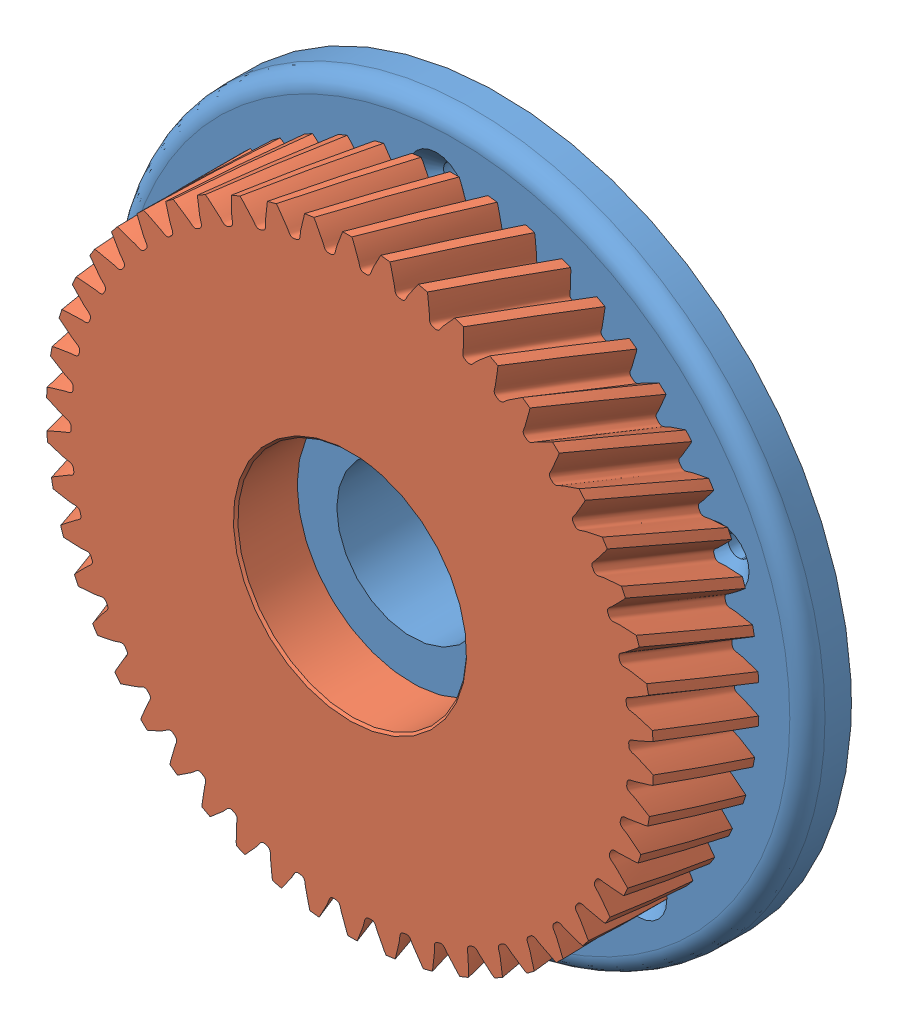
SolidWorks assembly Sun Gear Attachment, configuration Default. Lengths in mm.
Overall size (80.92 80.87 17).
2 component instances, 2 part files, 2 mates.
Components (placement in the parent):
- Attachment Detail-1: Attachment Detail [Default] at (-15.6766 35.7639 77.1895) size (80 80 10)
- Sun 50t-1: Sun 50t [Sun_Driver01] at (-15.6766 35.7639 85.6895) x (0.184269 0.982876 0) z (0 0 -1) size (69.28 69.34 12)
Mates (geometry in assembly coordinates):
- Coincident2: coincident anti-aligned: plane of Attachment Detail-1 through (-15.6766 35.7639 79.6895) normal (0 0 1); plane of Sun 50t-1 through (-15.6766 35.7639 79.6895) normal (0 0 -1)
- Concentric2: concentric aligned: cylinder of Attachment Detail-1 through (-15.6766 35.7639 79.6895) axis (0 0 -1) radius 8.5; cylinder of Sun 50t-1 through (-15.6766 35.7639 85.6895) axis (0 0 -1) radius 13
